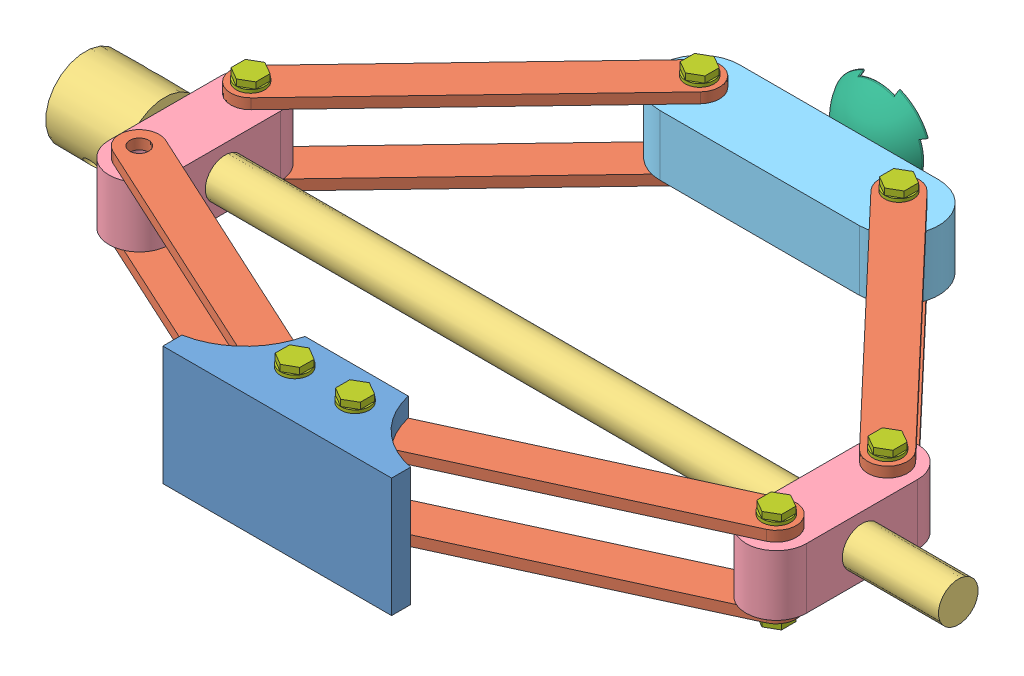
SolidWorks assembly Assem1, configuration Default. Lengths in mm.
Overall size (550.06 87 381.01).
29 component instances, 7 part files, 54 mates.
Components (placement in the parent):
- Part1-1: Part1 [Default] at (-9.1216 0.1126 157.0001) size (144 75 50)
- Part2-1: Part2 [Default] at (-209.7315 -25.3874 55.2274) x (0.908049 0 0.418863) z (0 1 0) size (225 25 6.5)
- Part 4-1: Part 4 [Default] at (-278.7014 0.1126 20.1683) x (-0.000679 -0.610637 0.79191) z (1 0 0.000857) size (50 50 550)
- Part5-1: Part5 [Default] at (191.6765 19.1126 20.5714) x (-0.000857 0 1) z (0 -1 0) size (108 38 38)
- Part6-1: Part6 [Default] at (-8.802 19.1126 -159.4023) x (1 0 0) z (0 -1 0) size (175.46 50 38)
- Part7-1: Part7 [Default] at (-8.802 0.1126 -171.9023) x (1 0 0) z (0 1 0) size (57.71 40.1 57.71)
- Part2-2: Part2 [Default] at (-209.7315 25.6126 55.2274) x (0.908049 0 0.418863) z (0 -1 0) size (225 25 6.5)
- Part2-3: Part2 [Default] at (9.8784 25.6126 139.0001) x (0.908841 0 -0.417144) z (0 -1 0) size (225 25 6.5)
- Part2-4: Part2 [Default] at (9.8784 -25.3874 139.0001) x (0.908841 0 -0.417144) z (0 1 0) size (225 25 6.5)
- Part2-5: Part2 [Default] at (53.9291 -18.8874 -159.4023) x (0.688887 0 0.724869) z (0 -1 0) size (225 25 6.5)
- Part2-6: Part2 [Default] at (-71.5331 19.1126 -159.4023) x (-0.690692 0 0.723149) z (0 1 0) size (225 25 6.5)
- Part5-2: Part5 [Default] at (-209.7015 19.1126 20.2275) x (-0.000857 0 1) z (0 -1 0) size (108 38 38)
- Part2-7: Part2 [Default] at (-71.5331 -18.8874 -159.4023) x (-0.690692 0 0.723149) z (0 -1 0) size (225 25 6.5)
- Part2-8: Part2 [Default] at (53.9291 19.1126 -159.4023) x (0.688887 0 0.724869) z (0 1 0) size (225 25 6.5)
- Part8-1: Part8 [Default] at (9.8784 -17.3874 139.0001) x (1 0 0) z (0 -1 0) size (18 18 26)
- Part8-2: Part8 [Default] at (9.8784 17.6126 139.0001) x (1 0 0) z (0 1 0) size (18 18 26)
- Part8-3: Part8 [Default] at (-28.1216 -17.3874 139.0001) x (1 0 0) z (0 -1 0) size (18 18 26)
- Part8-4: Part8 [Default] at (-209.6715 5.6126 -14.7725) x (1 0 0) z (0 1 0) size (18 18 26)
- Part8-5: Part8 [Default] at (191.7065 -5.3874 -14.4286) x (1 0 0) z (0 -1 0) size (18 18 26)
- Part8-6: Part8 [Default] at (-28.1216 17.6126 139.0001) x (0.999915 0 0.013013) z (0 1 0) size (18 18 26)
- Part8-7: Part8 [Default] at (-209.7315 -5.3874 55.2274) x (1 0 0) z (0 -1 0) size (18 18 26)
- Part8-8: Part8 [Default] at (191.6465 -5.3874 55.5714) x (1 0 0) z (0 -1 0) size (18 18 26)
- Part8-9: Part8 [Default] at (191.6465 5.6126 55.5714) x (1 0 0) z (0 1 0) size (18 18 26)
- Part8-10: Part8 [Default] at (191.7065 5.6126 -14.4286) x (1 0 0) z (0 1 0) size (18 18 26)
- Part8-11: Part8 [Default] at (-209.6715 -5.3874 -14.7725) x (1 0 0) z (0 -1 0) size (18 18 26)
- Part8-12: Part8 [Default] at (-71.5331 5.6126 -159.4023) x (1 0 0) z (0 1 0) size (18 18 26)
- Part8-13: Part8 [Default] at (-71.5331 -5.3874 -159.4023) x (1 0 0) z (0 -1 0) size (18 18 26)
- Part8-14: Part8 [Default] at (53.9291 -5.3874 -159.4023) x (-0.062695 0 0.998033) z (0 -1 0) size (18 18 26)
- Part8-15: Part8 [Default] at (53.9291 5.6126 -159.4023) x (1 0 0) z (0 1 0) size (18 18 26)
Mates (geometry in assembly coordinates):
- Coincident1: coincident: circle of Part1-1; circle of Part2-2
- Coincident2: coincident: circle of Part1-1; circle of Part2-3
- Coincident3: coincident: circle of Part1-1; circle of Part2-1
- Coincident4: coincident: circle of Part1-1; circle of Part2-4
- Coincident5: coincident: circle of Part2-2; circle of Part5-2
- Coincident6: coincident: circle of Part2-1; circle of Part5-2
- Coincident7: coincident: circle of Part5-1; circle of Part2-3
- Coincident11: coincident: circle of Part5-1; circle of Part2-4
- Coincident12: coincident: circle of Part5-1; circle of Part2-5
- Coincident13: coincident: circle of Part5-2; circle of Part2-7
- Coincident14: coincident: circle of Part5-1; circle of Part2-8
- Coincident15: coincident: circle of Part2-6; circle of Part5-2
- Concentric14: concentric: cylinder of Part 4-1 through (271.2984 0.1126 20.6396) axis (-1 0 -0.000857) radius 12.5; cylinder of Part5-2 through (-228.7015 0.1126 20.2112) axis (1 0 0.000857) radius 12
- Coincident42: coincident: plane of Part 4-1 through (-228.7015 0.1126 20.2112) normal (1 0 0.000857); plane of Part5-2 through (-228.6715 -18.8874 -14.7888) normal (-1 0 -0.000857)
- Concentric15: concentric: cylinder of Part 4-1 through (271.2984 0.1126 20.6396) axis (-1 0 -0.000857) radius 12.5; cylinder of Part5-1 through (172.6765 0.1126 20.5551) axis (1 0 0.000857) radius 12
- Concentric16: concentric: circle of Part6-1; circle of Part2-8
- Coincident43: coincident: plane of Part6-1 through (-71.5331 19.1126 -159.4023) normal (0 1 0); plane of Part2-8 through (53.9291 19.1126 -159.4023) normal (0 -1 0)
- Concentric17: concentric: circle of Part6-1; circle of Part2-8
- Concentric18: concentric: circle of Part6-1; circle of Part2-5
- Concentric19: concentric: circle of Part6-1; circle of Part2-7
- Concentric20: concentric: circle of Part6-1; circle of Part2-6
- Parallel8: parallel: plane of Part1-1 through (-9.1216 0.1126 157.0001) normal (0 0 -1); plane of Part6-1 through (-71.5331 -18.8874 -184.4023) normal (0 0 -1)
- Coincident47: coincident: plane of Part6-1 through (-8.802 0.1126 -171.9023) normal (0 0 -1); plane of Part7-1 through (-8.802 0.1126 -171.9023) normal (0 0 1)
- Concentric21: concentric: cylinder of Part6-1 through (-8.802 0.1126 -171.9023) axis (0 0 -1) radius 6; cylinder of Part7-1 through (-8.802 0.1126 -262.9033) axis (0 0 1) radius 6
- Concentric22: concentric: cylinder of Part1-1 through (-28.1216 -37.3874 139.0001) axis (0 1 0) radius 6; cylinder of Part8-6 through (-28.1216 37.6126 139.0001) axis (0 -1 0) radius 6
- Coincident48: coincident: plane of Part1-1 through (-81.1216 37.6126 169.0001) normal (0 1 0); plane of Part8-6 through (-28.1216 37.6126 139.0001) normal (0 -1 0)
- Concentric23: concentric: cylinder of Part1-1 through (9.8784 -37.3874 139.0001) axis (0 1 0) radius 6; cylinder of Part8-2 through (9.8784 37.6126 139.0001) axis (0 -1 0) radius 6
- Coincident49: coincident: plane of Part1-1 through (-81.1216 37.6126 169.0001) normal (0 1 0); plane of Part8-2 through (9.8784 37.6126 139.0001) normal (0 -1 0)
- Concentric24: concentric: cylinder of Part1-1 through (-28.1216 -37.3874 139.0001) axis (0 1 0) radius 6; cylinder of Part8-3 through (-28.1216 -37.3874 139.0001) axis (0 1 0) radius 6
- Coincident50: coincident: plane of Part1-1 through (-81.1216 -37.3874 169.0001) normal (0 -1 0); plane of Part8-3 through (-28.1216 -37.3874 139.0001) normal (0 1 0)
- Concentric25: concentric: cylinder of Part1-1 through (9.8784 -37.3874 139.0001) axis (0 1 0) radius 6; cylinder of Part8-1 through (9.8784 -37.3874 139.0001) axis (0 1 0) radius 6
- Coincident51: coincident: plane of Part1-1 through (-81.1216 -37.3874 169.0001) normal (0 -1 0); plane of Part8-1 through (9.8784 -37.3874 139.0001) normal (0 1 0)
- Concentric26: concentric: cylinder of Part5-2 through (-209.7315 -18.8874 55.2274) axis (0 1 0) radius 6; cylinder of Part8-7 through (-209.7315 -25.3874 55.2274) axis (0 1 0) radius 6
- Coincident52: coincident: plane of Part2-1 through (-209.7315 -25.3874 55.2274) normal (0 -1 0); plane of Part8-7 through (-209.7315 -25.3874 55.2274) normal (0 1 0)
- Concentric28: concentric: cylinder of Part2-7 through (-209.6715 -25.3874 -14.7725) axis (0 1 0) radius 6; cylinder of Part8-11 through (-209.6715 -25.3874 -14.7725) axis (0 1 0) radius 6
- Coincident53: coincident: plane of Part2-7 through (-71.5331 -25.3874 -159.4023) normal (0 -1 0); plane of Part8-11 through (-209.6715 -25.3874 -14.7725) normal (0 1 0)
- Concentric29: concentric: cylinder of Part2-6 through (-209.6715 25.6126 -14.7725) axis (0 -1 0) radius 6; cylinder of Part8-4 through (-209.6715 25.6126 -14.7725) axis (0 -1 0) radius 6
- Coincident54: coincident: plane of Part2-6 through (-71.5331 25.6126 -159.4023) normal (0 1 0); plane of Part8-4 through (-209.6715 25.6126 -14.7725) normal (0 -1 0)
- Concentric30: concentric: cylinder of Part2-4 through (191.6465 -18.8874 55.5714) axis (0 -1 0) radius 6; cylinder of Part8-8 through (191.6465 -25.3874 55.5714) axis (0 1 0) radius 6
- Coincident55: coincident: plane of Part2-4 through (9.8784 -25.3874 139.0001) normal (0 -1 0); plane of Part8-8 through (191.6465 -25.3874 55.5714) normal (0 1 0)
- Concentric31: concentric: cylinder of Part2-3 through (191.6465 19.1126 55.5714) axis (0 1 0) radius 6; cylinder of Part8-9 through (191.6465 25.6126 55.5714) axis (0 -1 0) radius 6
- Coincident56: coincident: plane of Part2-3 through (9.8784 25.6126 139.0001) normal (0 1 0); plane of Part8-9 through (191.6465 25.6126 55.5714) normal (0 -1 0)
- Concentric32: concentric: cylinder of Part2-5 through (191.7065 -25.3874 -14.4286) axis (0 1 0) radius 6; cylinder of Part8-5 through (191.7065 -25.3874 -14.4286) axis (0 1 0) radius 6
- Coincident57: coincident: plane of Part2-5 through (53.9291 -25.3874 -159.4023) normal (0 -1 0); plane of Part8-5 through (191.7065 -25.3874 -14.4286) normal (0 1 0)
- Concentric33: concentric: cylinder of Part2-8 through (191.7065 25.6126 -14.4286) axis (0 -1 0) radius 6; cylinder of Part8-10 through (191.7065 25.6126 -14.4286) axis (0 -1 0) radius 6
- Coincident58: coincident: plane of Part2-8 through (53.9291 25.6126 -159.4023) normal (0 1 0); plane of Part8-10 through (191.7065 25.6126 -14.4286) normal (0 -1 0)
- Concentric34: concentric: cylinder of Part2-8 through (53.9291 25.6126 -159.4023) axis (0 -1 0) radius 6; cylinder of Part8-15 through (53.9291 25.6126 -159.4023) axis (0 -1 0) radius 6
- Coincident59: coincident: plane of Part2-8 through (53.9291 25.6126 -159.4023) normal (0 1 0); plane of Part8-15 through (53.9291 25.6126 -159.4023) normal (0 -1 0)
- Concentric35: concentric: cylinder of Part2-5 through (53.9291 -25.3874 -159.4023) axis (0 1 0) radius 6; cylinder of Part8-14 through (53.9291 -25.3874 -159.4023) axis (0 1 0) radius 6
- Coincident60: coincident: plane of Part2-5 through (53.9291 -25.3874 -159.4023) normal (0 -1 0); plane of Part8-14 through (53.9291 -25.3874 -159.4023) normal (0 1 0)
- Concentric37: concentric: cylinder of Part2-6 through (-71.5331 25.6126 -159.4023) axis (0 -1 0) radius 6; cylinder of Part8-12 through (-71.5331 25.6126 -159.4023) axis (0 -1 0) radius 6
- Coincident61: coincident: plane of Part2-6 through (-71.5331 25.6126 -159.4023) normal (0 1 0); plane of Part8-12 through (-71.5331 25.6126 -159.4023) normal (0 -1 0)
- Concentric38: concentric: cylinder of Part2-7 through (-71.5331 -25.3874 -159.4023) axis (0 1 0) radius 6; cylinder of Part8-13 through (-71.5331 -25.3874 -159.4023) axis (0 1 0) radius 6
- Coincident62: coincident: plane of Part2-7 through (-71.5331 -25.3874 -159.4023) normal (0 -1 0); plane of Part8-13 through (-71.5331 -25.3874 -159.4023) normal (0 1 0)
